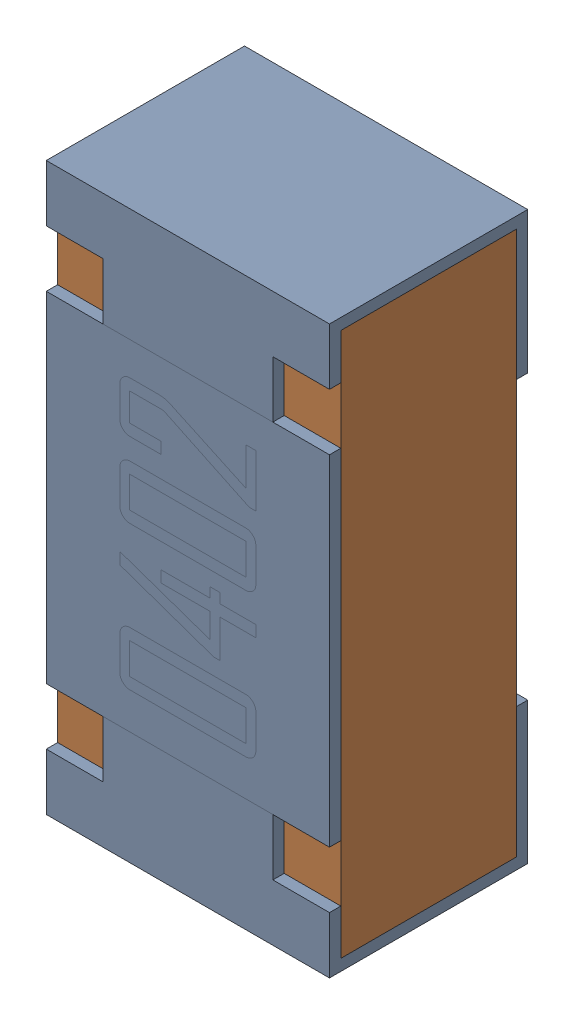
SolidWorks assembly R8, configuration Default. Lengths in mm.
Overall size (0.5 1 0.35).
3 component instances, 2 part files, 0 mates.
Components (placement in the parent):
- R8-subassembly-1-1: R8-subassembly-1 [Default] at (-10.5 7.7499 0) x (0 1 0) z (1 0 0) size (1 0.35 0.5)
  - 0402 resistor-1: 0402 resistor [Default] at origin size (1 0.35 0.5)
  - 0402 resistor-1-1: 0402 resistor-1 [Default] at origin size (0.96 0.31 0.5)
